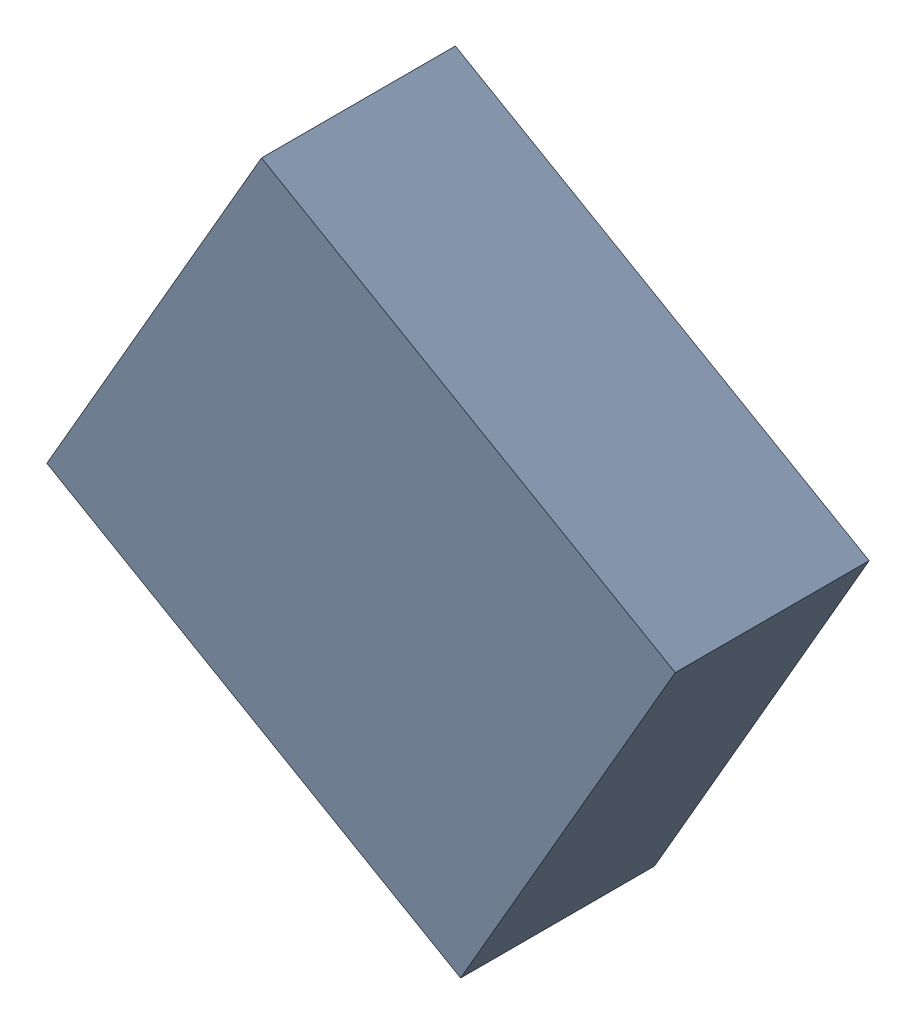
SolidWorks assembly F1_TDA3, configuration Standard. Lengths in mm.
Overall size (4.54 4.41 1.4).
2 component instances, 1 part files, 0 mates.
Components (placement in the parent):
- 885544960-1: 885544960 [Standard] at (49.9743 -27.7332 0) size (4.54 4.41 1.4)
  - Extruded_3-1: Extruded_3 [Standard] at origin size (4.54 4.41 1.4)
